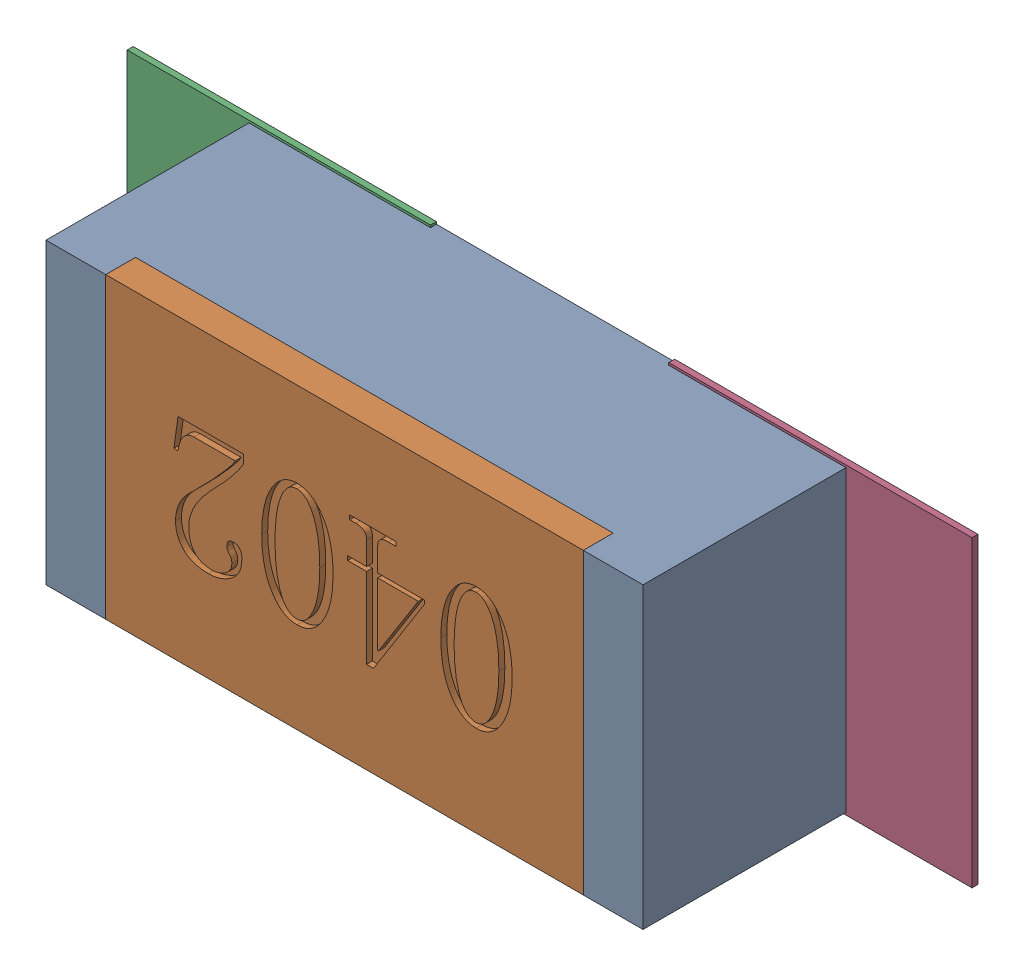
SolidWorks assembly R2, configuration Défaut. Lengths in mm.
Overall size (1.42 0.51 0.35).
5 component instances, 2 part files, 0 mates.
Components (placement in the parent):
- R0402-1: R0402 [Défaut] at (55.1942 -19.3801 0) x (-1 0 0) z (0 0 1) size (1 0.5 0.35)
- 6504207776-1: 6504207776 [Défaut] at (54.7442 -19.3802 0) size (0.51 0.51 0.01)
  - Extruded-1: Extruded [Défaut] at origin size (0.51 0.51 0.01)
- 6504207776-2: 6504207776 [Défaut] at (55.6513 -19.3802 0) size (0.51 0.51 0.01)
  - Extruded-1: Extruded [Défaut] at origin size (0.51 0.51 0.01)
